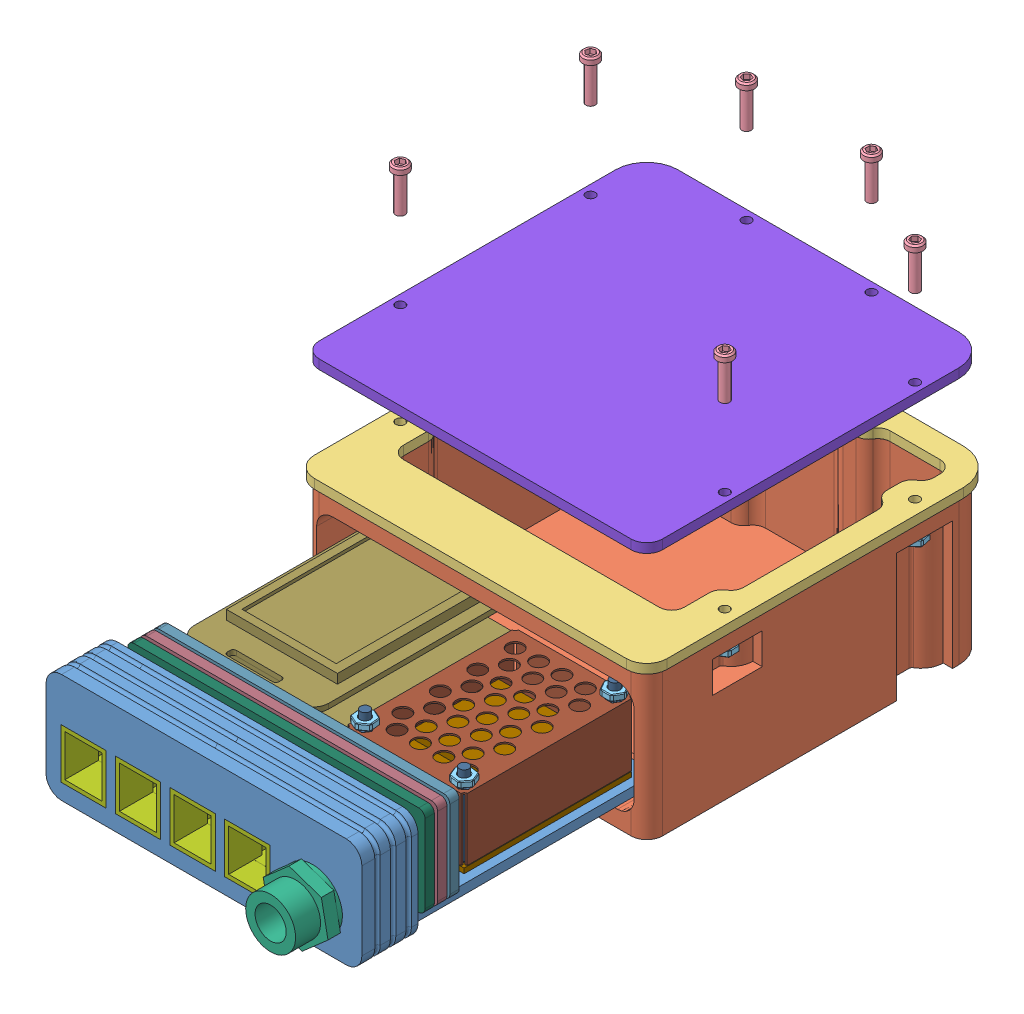
SolidWorks assembly Update5, configuration Default. Lengths in mm.
Overall size (113.02 122.11 234.42).
35 component instances, 16 part files, 76 mates.
Components (placement in the parent):
- Copy of Tray^Update5-1: Copy of Tray^Update5 [Default] at (-1.625 -9.25 -26.0756) size (101.25 35 100) (virtual)
- Body-1: Body [Default] at origin size (110 47 134)
- Rubber Seal-1: Rubber Seal [Default] at (4.0261 669.5896 2.3537) x (1 0 0) z (0 1 0) size (113 113 3)
- Bolt-1: Bolt [Default] at (116.399 93.1131 -100.3508) x (0.618334 0 -0.785915) z (0.785915 0 0.618334) size (5 14 5)
- Bolt-2: Bolt [Default] at (89.1652 93.1131 -58.9149) x (0.999414 0 0.034242) z (-0.034242 0 0.999414) size (5 14 5)
- Bolt-3: Bolt [Default] at (-92.3745 93.1131 -366.7664) x (-0.977927 0 -0.208948) z (0.208948 0 -0.977927) size (5 14 5)
- Bolt-4: Bolt [Default] at (142.4243 93.1131 -284.9664) x (-0.541782 0 -0.840519) z (0.840519 0 -0.541782) size (5 14 5)
- Bolt-5: Bolt [Default] at (48.7729 93.1131 -375.2621) x (-0.655005 0 -0.755624) z (0.755624 0 -0.655005) size (5 14 5)
- Bolt-6: Bolt [Default] at (8.0153 93.1131 -32.1437) x (0.761992 0 0.647586) z (-0.647586 0 0.761992) size (5 14 5)
- Nut-1: Nut [Default] at (92.4734 11.7498 44.9404) x (0.98358 0 -0.18047) z (0 1 0) size (6.19 6.69 2)
- Nut-2: Nut [Default] at (206.2749 11.7498 -357.1508) x (-0.157377 0 -0.987539) z (0 1 0) size (6.19 6.69 2)
- Nut-3: Nut [Default] at (-179.6689 11.7498 -163.8703) x (-0.563149 0 0.826356) z (0 1 0) size (6.19 6.69 2)
- Nut-4: Nut [Default] at (-238.4369 11.7498 -59.0678) x (0.156235 0 0.98772) z (0 1 0) size (6.19 6.69 2)
- Nut-5: Nut [Default] at (155.3941 11.7498 -407.9244) x (-0.584501 0 -0.811393) z (0 1 0) size (6.19 6.69 2)
- Nut-6: Nut [Default] at (89.0859 11.7498 -10.9932) x (1 0 0) z (0 1 0) size (6.19 6.69 2)
- CableGland_1-3: CableGland_1 [Default] at (34.875 -8.5 -17.5756) x (-0.952935 0.303174 0) z (0 0 -1) size (21.93 19.22 20)
- RJ45-6: RJ45 [Default] at (6.625 -0.5 -23.0756) x (1 0 0) z (0 0 -1) size (16.81 16.01 33.66)
- Part5^Update5-1: Part5^Update5 [Default] at origin (virtual)
- Acrylic_lid_latest-1: Acrylic_lid_latest [Default] at (4.6351 273.0609 73.8303) size (110 3 110)
- RJ45-7: RJ45 [Default] at (3.625 -16.5 -23.0756) x (-1 0 0) z (0 0 -1) size (16.81 16.01 33.66)
- RJ45-9: RJ45 [Default] at (-31.375 -16.5 -23.0756) x (-1 0 0) z (0 0 -1) size (16.81 16.01 33.66)
- RJ45-10: RJ45 [Default] at (-13.875 -16.5 -23.0756) x (-1 0 0) z (0 0 -1) size (16.81 16.01 33.66)
- Part180^Update5-1: Part180^Update5 [Default] at (-1.625 -18.5 -26.0756) x (1 0 0) z (0 1 0) size (37.21 53.59 13.2) (virtual)
- Part183^Update5-1: Part183^Update5 [Default] at (37.304 -24.1367 -51.2049) x (0.979312 0 -0.202354) z (0 1 0) size (4.48 4.44 33) (virtual)
- Part183^Update5-3: Part183^Update5 [Default] at (62.8776 -24.1367 -42.9607) x (0.994245 0 0.107134) z (0 1 0) size (4.48 4.44 33) (virtual)
- Part183^Update5-4: Part183^Update5 [Default] at (12.3097 -24.1367 -96.1638) x (-0.272474 0 0.962163) z (0 1 0) size (4.48 4.44 33) (virtual)
- Part184^Update5-1: Part184^Update5 [Default] at (121.8531 3.3201 -42.9283) x (1 0 0) z (0 1 0) size (38.21 54.59 20) (virtual)
- Nut-7: Nut [Default] at (-176.897 4.7693 -28.8142) x (-0.107896 0 0.994162) z (0 1 0) size (6.19 6.69 2)
- Nut-8: Nut [Default] at (201.5626 4.7693 100.9556) x (0.960869 0 -0.277003) z (0 1 0) size (6.19 6.69 2)
- Nut-9: Nut [Default] at (117.0159 4.7693 139.2341) x (1 0 0) z (0 1 0) size (6.19 6.69 2)
- Part185^Update5-1: Part185^Update5 [Default] at (104.6497 -15.3159 -60.9946) size (43.17 27.8 66) (virtual)
- Assem1-1: Assem1 [Default] at (0 0 -6.0292) size (95.25 29 3)
  - Copy of Part186-1: Copy of Part186 [Default] at (-1.625 -9.25 -44.3156) x (-1 0 0) z (0 0 -1) size (95.25 29 3)
- Copy (2) of Part186^Update5-1: Copy (2) of Part186^Update5 [Default] at (-1.625 -9.25 -54.2634) x (-1 0 0) z (0 0 -1) size (95.25 29 3) (virtual)
- Copy of Part186^Update5-1: Copy of Part186^Update5 [Default] at (-1.625 -9.25 -46.283) x (-1 0 0) z (0 0 -1) size (95.25 29 3) (virtual)
Mates (geometry in assembly coordinates):
- Concentric2: concentric anti-aligned: cylinder of Body-1 through (-20 20 -217.003) axis (0 -1 0) radius 1.5; cylinder of Bolt-5 through (-20 81.1131 -217.003) axis (0 1 0) radius 1.5
- Concentric3: concentric anti-aligned: cylinder of Body-1 through (-52 20 -199) axis (0 -1 0) radius 1.5; cylinder of Bolt-3 through (-52 81.1131 -199) axis (0 1 0) radius 1.5
- Concentric4: concentric anti-aligned: cylinder of Body-1 through (-52 20 -138) axis (0 -1 0) radius 1.5; cylinder of Bolt-1 through (-52 81.1131 -138) axis (0 1 0) radius 1.5
- Concentric6: concentric anti-aligned: cylinder of Body-1 through (52 20 -199) axis (0 -1 0) radius 1.5; cylinder of Bolt-6 through (52 81.1131 -199) axis (0 1 0) radius 1.5
- Concentric7: concentric anti-aligned: cylinder of Body-1 through (20 20 -217.003) axis (0 -1 0) radius 1.5; cylinder of Bolt-2 through (20 81.1131 -217.003) axis (0 1 0) radius 1.5
- Coincident10: coincident aligned: plane of Bolt-2 through (89.1652 93.6131 -58.9149) normal (0 1 0); plane of Bolt-5 through (48.7729 93.6131 -375.2621) normal (0 1 0)
- Coincident11: coincident aligned: plane of Bolt-3 through (-92.3745 93.6131 -366.7664) normal (0 1 0); plane of Bolt-5 through (48.7729 93.6131 -375.2621) normal (0 1 0)
- Coincident12: coincident aligned: plane of Bolt-3 through (-92.3745 93.6131 -366.7664) normal (0 1 0); plane of Bolt-6 through (8.0153 93.6131 -32.1437) normal (0 1 0)
- Coincident13: coincident aligned: plane of Bolt-4 through (142.4243 93.6131 -284.9664) normal (0 1 0); plane of Bolt-6 through (8.0153 93.6131 -32.1437) normal (0 1 0)
- Coincident14: coincident aligned: plane of Bolt-1 through (116.399 93.6131 -100.3508) normal (0 1 0); plane of Bolt-4 through (142.4243 93.6131 -284.9664) normal (0 1 0)
- Concentric8: concentric anti-aligned: cylinder of Bolt-1 through (-52 81.1131 -138) axis (0 1 0) radius 1.5; cylinder of Nut-1 through (-52 13.7498 -138) axis (0 -1 0) radius 1.5
- Concentric9: concentric anti-aligned: cylinder of Bolt-3 through (-52 81.1131 -199) axis (0 1 0) radius 1.5; cylinder of Part4^Update5-4 through (-52 13.7498 -199) axis (0 -1 0) radius 1.5
- Concentric10: concentric anti-aligned: cylinder of Bolt-5 through (-20 81.1131 -217.003) axis (0 1 0) radius 1.5; cylinder of Part4^Update5-6 through (-20 13.7498 -217.003) axis (0 -1 0) radius 1.5
- Concentric11: concentric anti-aligned: cylinder of Bolt-2 through (20 81.1131 -217.003) axis (0 1 0) radius 1.5; cylinder of Part4^Update5-2 through (20 13.7498 -217.003) axis (0 -1 0) radius 1.5
- Concentric13: concentric anti-aligned: cylinder of Bolt-6 through (52 81.1131 -199) axis (0 1 0) radius 1.5; cylinder of Part4^Update5-5 through (52 13.7498 -199) axis (0 -1 0) radius 1.5
- Coincident15: coincident aligned: plane of Part4^Update5-3 through (-179.6689 11.7498 -163.8703) normal (0 -1 0); plane of Part4^Update5-5 through (155.3941 11.7498 -407.9244) normal (0 -1 0)
- Coincident16: coincident aligned: plane of Part4^Update5-2 through (206.2749 11.7498 -357.1508) normal (0 -1 0); plane of Part4^Update5-5 through (155.3941 11.7498 -407.9244) normal (0 -1 0)
- Coincident17: coincident aligned: plane of Part4^Update5-2 through (206.2749 11.7498 -357.1508) normal (0 -1 0); plane of Part4^Update5-6 through (89.0859 11.7498 -10.9932) normal (0 -1 0)
- Coincident18: coincident aligned: plane of Part4^Update5-4 through (-238.4369 11.7498 -59.0678) normal (0 -1 0); plane of Part4^Update5-6 through (89.0859 11.7498 -10.9932) normal (0 -1 0)
- Coincident19: coincident aligned: plane of Nut-1 through (92.4734 11.7498 44.9404) normal (0 -1 0); plane of Part4^Update5-4 through (-238.4369 11.7498 -59.0678) normal (0 -1 0)
- Coincident32: coincident anti-aligned: plane of Copy of Tray^Update5-1 through (45.625 -16.5 -23.0756) normal (0 0 1); plane of CableGland_1-3 through (34.875 -8.5 -23.0756) normal (0 0 -1)
- Concentric18: concentric anti-aligned: cylinder of Copy of Tray^Update5-1 through (34.875 -8.5 -23.0756) axis (0 0 -1) radius 8; cylinder of CableGland_1-3 through (34.875 -8.5 -29.5756) axis (0 0 1) radius 8
- Coincident44: coincident anti-aligned: plane of Copy of Tray^Update5-1 through (6.625 -0.5 -23.0756) normal (1 0 0); plane of RJ45-6 through (6.625 -0.5 -32.4756) normal (-1 0 0)
- Coincident45: coincident anti-aligned: plane of Copy of Tray^Update5-1 through (6.625 -0.5 -23.0756) normal (0 -1 0); plane of RJ45-6 through (6.625 -0.5 -32.4756) normal (0 1 0)
- Parallel2: parallel aligned: line of Copy of Tray^Update5-1 through (6.625 -0.5 -26.0756) axis (1 0 0); line of RJ45-6 through (5.4675 -0.4863 -32.4756) axis (1 0 0)
- Parallel3: parallel anti-aligned: line of Copy of Tray^Update5-1 through (21.125 -0.5 -23.0756) axis (-1 0 0); line of RJ45-6 through (5.4675 -0.4863 -32.4756) axis (1 0 0)
- Coincident48: coincident anti-aligned: line of Copy of Tray^Update5-1 through (21.125 -16.5 -23.0756) axis (0 1 0); line of RJ45-6 through (21.125 -0.5 -23.0756) axis (0 -1 0)
- Coincident67: coincident anti-aligned: plane of Copy of Tray^Update5-1 through (-10.875 -0.5 -23.0756) normal (0 -1 0); plane of RJ45-7 through (3.625 -0.5 -32.4756) normal (0 1 0)
- Coincident69: coincident anti-aligned: plane of Copy of Tray^Update5-1 through (-10.875 -0.5 -23.0756) normal (1 0 0); plane of RJ45-7 through (-10.875 -16.5 -32.4756) normal (-1 0 0)
- Coincident70: coincident aligned: plane of Copy of Tray^Update5-1 through (45.625 -16.5 -23.0756) normal (0 0 1); plane of RJ45-7 through (3.625 -16.5 -23.0756) normal (0 0 1)
- Coincident72: coincident anti-aligned: plane of Copy of Tray^Update5-1 through (-28.375 -0.5 -23.0756) normal (1 0 0); plane of RJ45-10 through (-28.375 -16.5 -32.4756) normal (-1 0 0)
- Coincident73: coincident: line of Copy of Tray^Update5-1 through (-28.375 -16.5 -26.0756) axis (1 0 0); plane of RJ45-10 through (-13.875 -16.5 -32.4756) normal (0 -1 0)
- Coincident75: coincident aligned: plane of Copy of Tray^Update5-1 through (45.625 -16.5 -23.0756) normal (0 0 1); plane of RJ45-10 through (-13.875 -16.5 -23.0756) normal (0 0 1)
- Coincident76: coincident anti-aligned: plane of Copy of Tray^Update5-1 through (-45.875 -0.5 -23.0756) normal (1 0 0); plane of RJ45-9 through (-45.875 -16.5 -32.4756) normal (-1 0 0)
- Coincident77: coincident anti-aligned: plane of Copy of Tray^Update5-1 through (-45.875 -0.5 -23.0756) normal (0 -1 0); plane of RJ45-9 through (-31.375 -0.5 -32.4756) normal (0 1 0)
- Coincident78: coincident aligned: plane of Copy of Tray^Update5-1 through (45.625 -16.5 -23.0756) normal (0 0 1); plane of RJ45-9 through (-31.375 -16.5 -23.0756) normal (0 0 1)
- Coincident80: coincident aligned: plane of Copy of Tray^Update5-1 through (45.625 -16.5 -109.7286) normal (0 0 1); plane of Body-1 through (-50 -27 -110) normal (0 0 1)
- Concentric27: concentric aligned: cylinder of Body-1 through (-52 20 -199) axis (0 -1 0) radius 1.5; cylinder of Rubber Seal-1 through (-52 23 -199) axis (0 -1 0) radius 1.5
- Concentric28: concentric aligned: cylinder of Body-1 through (52 20 -138) axis (0 -1 0) radius 1.5; cylinder of Rubber Seal-1 through (52 23 -138) axis (0 -1 0) radius 1.5
- Coincident83: coincident aligned: plane of Body-1 through (55 -27 -210) normal (1 0 0); plane of Acrylic_lid-1 through (55 55.4413 -210) normal (1 0 0)
- Parallel7: parallel aligned: plane of Body-1 through (-50 -27 -110) normal (0 0 1); plane of Acrylic_lid-1 through (-50 55.4413 -110) normal (0 0 1)
- Concentric30: concentric anti-aligned: cylinder of Body-1 through (50 -27 -115) axis (0 1 0) radius 5; cylinder of Acrylic_lid-1 through (50 55.4413 -115) axis (0 -1 0) radius 5
- Concentric31: concentric anti-aligned: cylinder of Rubber Seal-1 through (52 23 -138) axis (0 -1 0) radius 1.5; cylinder of Bolt-4 through (52 81.1131 -138) axis (0 1 0) radius 1.5
- Concentric32: concentric aligned: cylinder of Body-1 through (52 20 -138) axis (0 -1 0) radius 1.5; cylinder of Nut-3 through (52 13.7498 -138) axis (0 -1 0) radius 1.5
- InPlace1: in place: plane of ? through (45.625 -18.5 6.9747) normal (0 1 0); plane of ? through (0 -18.5 0) normal (0 1 0); moOrthogonalPlaneRef_w of ? through (45.625 -18.5 6.9747) normal (0 1 0); plane of ? through (0 -18.5 0) normal (0 0 -1); plane of ? through (45.625 -18.5 6.9747) normal (0 1 0); plane of ? through (0 -18.5 0) normal (1 0 0); plane of Copy of Tray^Update5-1 through (45.625 -18.5 -41.0756) normal (0 1 0); unknown of Part180^Update5-1
- Coincident87: coincident aligned: plane of ?; plane of ?
- Coincident88: coincident aligned: moOrthogonalPlaneRef_w of Copy of Tray^Update5-1 through (-1.625 -18.5 -26.0756) normal (0 0 -1); plane of Part180^Update5-1 through (-1.625 -18.5 -26.0756) normal (0 0 -1)
- Coincident89: coincident anti-aligned: moOrthogonalPlaneRef_w of Copy of Tray^Update5-1 through (-1.625 -18.5 -26.0756) normal (-1 0 0); plane of Part180^Update5-1 through (-1.625 -18.5 -26.0756) normal (1 0 0)
- Lock1: lock: unknown of Copy of Tray^Update5-1; unknown of Part180^Update5-1
- Lock2: lock: unknown of Copy of Tray^Update5-1; unknown of Part180^Update5-1
- Concentric35: concentric anti-aligned: cylinder of Part180^Update5-1 through (39.68 -18.5 -115.0356) axis (0 1 0) radius 1.5; cylinder of Part183^Update5-4 through (39.68 -16.1367 -115.0356) axis (0 -1 0) radius 1.5
- Concentric36: concentric anti-aligned: cylinder of Part180^Update5-1 through (39.68 -18.5 -66.7756) axis (0 1 0) radius 1.5; cylinder of Part183^Update5-3 through (39.68 -16.1367 -66.7756) axis (0 -1 0) radius 1.5
- Concentric37: concentric anti-aligned: cylinder of Part180^Update5-1 through (7.93 -18.5 -66.7756) axis (0 1 0) radius 1.5; cylinder of Part183^Update5-1 through (7.93 -16.1367 -66.7756) axis (0 -1 0) radius 1.5
- Coincident101: coincident aligned: plane of Part183^Update5-1 through (7.93 8.8633 -66.7756) normal (0 1 0); plane of Part183^Update5-3 through (39.68 8.8633 -66.7756) normal (0 1 0)
- Coincident102: coincident aligned: plane of Part183^Update5-3 through (39.68 8.8633 -66.7756) normal (0 1 0); plane of Part183^Update5-4 through (39.68 8.8633 -115.0356) normal (0 1 0)
- Concentric39: concentric aligned: cylinder of Part183^Update5-4 through (39.68 8.8633 -115.0356) axis (0 -1 0) radius 1.5; cylinder of Part184^Update5-1 through (39.68 3.8201 -115.0356) axis (0 -1 0) radius 1.5
- Concentric40: concentric aligned: cylinder of Part183^Update5-3 through (39.68 8.8633 -66.7756) axis (0 -1 0) radius 1.5; cylinder of Part184^Update5-1 through (39.68 3.8201 -66.7756) axis (0 -1 0) radius 1.5
- Concentric41: concentric aligned: cylinder of Part183^Update5-4 through (39.68 8.8633 -115.0356) axis (0 -1 0) radius 1.5; cylinder of Nut-7 through (39.68 6.7693 -115.0356) axis (0 -1 0) radius 1.5
- Concentric42: concentric aligned: cylinder of Part183^Update5-3 through (39.68 8.8633 -66.7756) axis (0 -1 0) radius 1.5; cylinder of Nut-8 through (39.68 6.7693 -66.7756) axis (0 -1 0) radius 1.5
- Concentric43: concentric aligned: cylinder of Part183^Update5-1 through (7.93 8.8633 -66.7756) axis (0 -1 0) radius 1.5; cylinder of Nut-9 through (7.93 6.7693 -66.7756) axis (0 -1 0) radius 1.5
- Coincident106: coincident aligned: plane of Nut-8 through (201.5626 6.7693 100.9556) normal (0 1 0); plane of Nut-9 through (117.0159 6.7693 139.2341) normal (0 1 0)
- Coincident107: coincident aligned: plane of Nut-7 through (-176.897 6.7693 -28.8142) normal (0 1 0); plane of Nut-8 through (201.5626 6.7693 100.9556) normal (0 1 0)
- Lock4: lock: unknown of Copy of Tray^Update5-1; unknown of Part185^Update5-1
- Parallel10: parallel anti-aligned: plane of Copy of Tray^Update5-1 through (45.625 10.5 -41.0756) normal (0 -1 0); plane of Assem1-1/Copy of Part186-1 through (-1.625 10.5 -53.3449) normal (0 1 0)
- Coincident119: coincident anti-aligned: plane of Copy of Tray^Update5-1 through (47.625 8.5 -41.0756) normal (-1 0 0); plane of Assem1-1/Copy of Part186-1 through (47.625 -9.25 -53.3449) normal (1 0 0)
- Concentric48: concentric aligned: cylinder of Copy of Tray^Update5-1 through (-45.625 8.5 -41.0756) axis (0 0 1) radius 2; cylinder of Assem1-1/Copy of Part186-1 through (-45.625 8.5 -53.3449) axis (0 0 1) radius 2
- Coincident120: coincident aligned: plane of Assem1-1/Copy of Part186-1 through (47.625 -9.25 -53.3449) normal (1 0 0); plane of Copy of Part186^Update5-1 through (47.625 -9.25 -49.283) normal (1 0 0)
- Coincident121: coincident aligned: plane of Assem1-1/Copy of Part186-1 through (-1.625 10.5 -53.3449) normal (0 1 0); plane of Copy of Part186^Update5-1 through (-1.625 10.5 -49.283) normal (0 1 0)
- Coincident122: coincident aligned: plane of Assem1-1/Copy of Part186-1 through (-1.625 10.5 -53.3449) normal (0 1 0); plane of Copy (2) of Part186^Update5-1 through (-1.625 10.5 -57.2634) normal (0 1 0)
- Coincident123: coincident aligned: plane of Assem1-1/Copy of Part186-1 through (47.625 -9.25 -53.3449) normal (1 0 0); plane of Copy (2) of Part186^Update5-1 through (47.625 -9.25 -57.2634) normal (1 0 0)
- Lock7: lock: unknown of Assem1-1/Copy of Part186-1; unknown of Copy (2) of Part186^Update5-1
- Lock8: lock: unknown of Assem1-1/Copy of Part186-1; unknown of Copy of Part186^Update5-1
- Concentric49: concentric anti-aligned: cylinder of Copy of Tray^Update5-1 through (-45.625 8.5 -23.0756) axis (0 0 -1) radius 5; cylinder of Body-1 through (-45.625 8.5 -128) axis (0 0 1) radius 5.25
- Concentric50: concentric anti-aligned: cylinder of Copy of Tray^Update5-1 through (45.625 8.5 -23.0756) axis (0 0 -1) radius 5; cylinder of Body-1 through (45.625 8.5 -128) axis (0 0 1) radius 5.25
- Concentric51: concentric anti-aligned: cylinder of Copy of Tray^Update5-1 through (45.625 -16.5 -23.0756) axis (0 0 -1) radius 5; cylinder of Body-1 through (45.625 -16.5 -128) axis (0 0 1) radius 5.25
- Concentric52: concentric anti-aligned: cylinder of Copy of Tray^Update5-1 through (-45.625 -16.5 -23.0756) axis (0 0 -1) radius 5; cylinder of Body-1 through (-45.625 -16.5 -128) axis (0 0 1) radius 5.25
